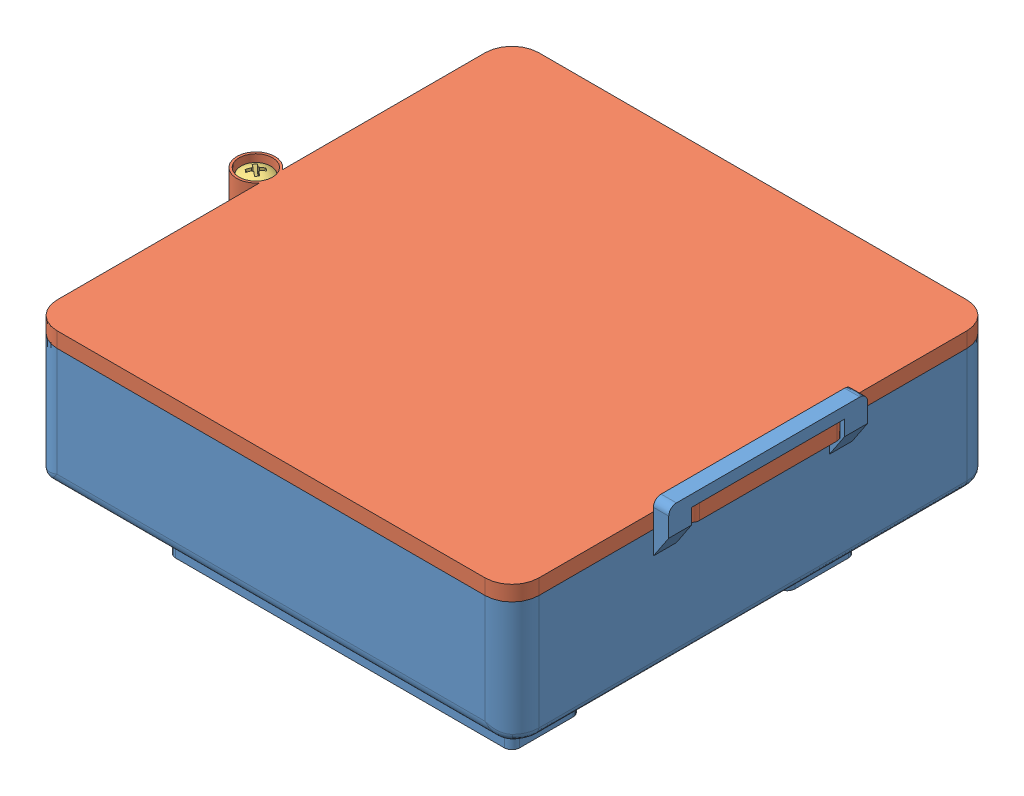
SolidWorks assembly Subconjunto caixa pilhas, configuration Default. Lengths in mm.
Overall size (69.81 28.5 63).
3 component instances, 3 part files, 5 mates.
Components (placement in the parent):
- Caixa das pilhas-1: Caixa das pilhas [Default] at (12.7241 32.9375 62.5857) size (69.5 28.5 63)
- Tampa compartimento das pilhas-1: Tampa compartimento das pilhas [Default] at (12.7241 42.9375 62.5857) x (0 0 1) z (1 0 0) size (63 4 69.5)
- pan head cross recess screw_iso-4: pan head cross recess screw_iso [ISO 7045 - M2 x 6 - Z - 6N] at (-20.7759 42.7775 62.5857) x (0 -1 0) z (0.784317 0 0.62036) size (7.57 4 4)
Mates (geometry in assembly coordinates):
- Concentric1: concentric aligned: cylinder of Caixa das pilhas-1 through (-20.7759 33.9375 62.5857) axis (0 1 0) radius 2.5; cylinder of Tampa compartimento das pilhas-1 through (-20.7759 38.9375 62.5857) axis (0 1 0) radius 2.5
- Concentric2: concentric anti-aligned: cylinder of Caixa das pilhas-1 through (-15.2759 40.9375 34.5857) axis (0 -1 0) radius 3.5; cylinder of Tampa compartimento das pilhas-1 through (-15.2759 40.9375 34.5857) axis (0 1 0) radius 3.5
- Coincident1: coincident anti-aligned: plane of Caixa das pilhas-1 through (-20.7759 38.9375 62.5857) normal (0 1 0); plane of Tampa compartimento das pilhas-1 through (-20.7759 38.9375 62.5857) normal (0 -1 0)
- Concentric9: concentric aligned: cylinder of Caixa das pilhas-1 through (-20.7759 38.9375 62.5857) axis (0 1 0) radius 0.8; cylinder of pan head cross recess screw_iso-4 through (-20.7759 68.1775 62.5857) axis (0 1 0) radius 1
- Coincident5: coincident anti-aligned: plane of Tampa compartimento das pilhas-1 through (-20.7759 41.1775 63.7857) normal (0 1 0); plane of pan head cross recess screw_iso-4 through (-20.1555 41.1775 61.8013) normal (0 -1 0)
